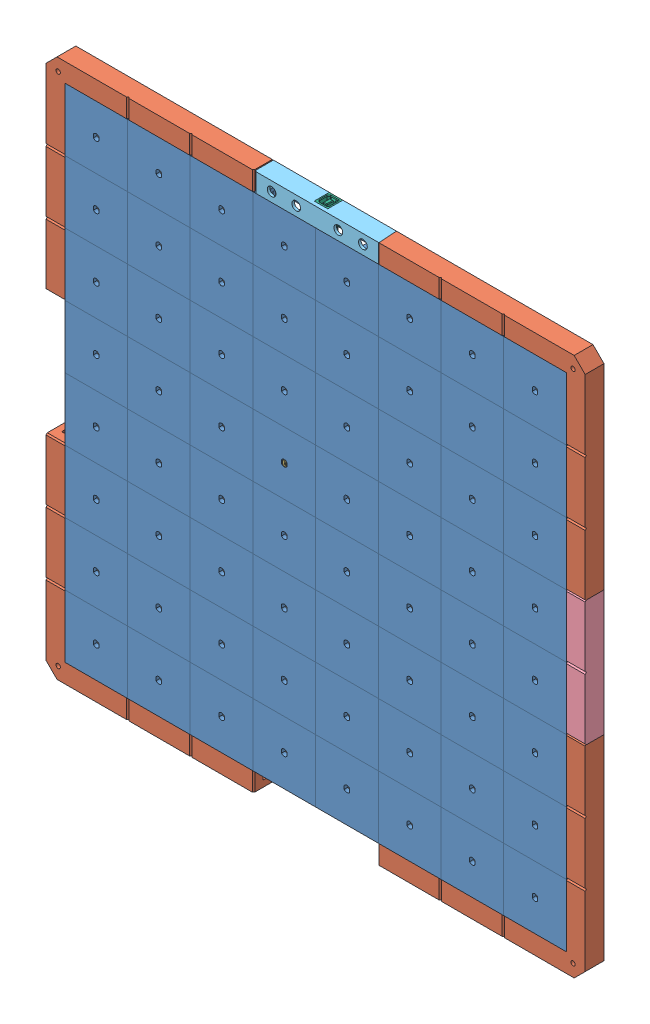
SolidWorks assembly ChessBoardAssem, configuration Default. Lengths in mm.
Overall size (430 430 16.78).
72 component instances, 6 part files, 162 mates.
Components (placement in the parent):
- ChessField-1: ChessField [Default] at (20.7333 30.8227 34.0737) size (50 50 15)
- ChessField-3: ChessField [Default] at (320.7333 30.8227 34.0737) size (50 50 15)
- ChessField-6: ChessField [Default] at (320.7333 80.8227 34.0737) size (50 50 15)
- ChessField-8: ChessField [Default] at (370.7333 130.8227 34.0737) size (50 50 15)
- ChessField-9: ChessField [Default] at (220.7333 30.8227 34.0737) size (50 50 15)
- ChessField-10: ChessField [Default] at (370.7333 80.8227 34.0737) size (50 50 15)
- ChessField-11: ChessField [Default] at (70.7333 80.8227 34.0737) size (50 50 15)
- ChessField-12: ChessField [Default] at (270.7333 30.8227 34.0737) size (50 50 15)
- ChessField-13: ChessField [Default] at (120.7333 30.8227 34.0737) size (50 50 15)
- ChessField-14: ChessField [Default] at (370.7333 180.8227 34.0737) size (50 50 15)
- ChessField-16: ChessField [Default] at (70.7333 30.8227 34.0737) size (50 50 15)
- ChessField-18: ChessField [Default] at (170.7333 80.8227 34.0737) size (50 50 15)
- ChessField-20: ChessField [Default] at (170.7333 130.8227 34.0737) size (50 50 15)
- ChessField-21: ChessField [Default] at (270.7333 130.8227 34.0737) size (50 50 15)
- ChessField-25: ChessField [Default] at (320.7333 180.8227 34.0737) size (50 50 15)
- ChessField-29: ChessField [Default] at (220.7333 180.8227 34.0737) size (50 50 15)
- ChessField-34: ChessField [Default] at (220.7333 80.8227 34.0737) size (50 50 15)
- ChessField-38: ChessField [Default] at (120.7333 130.8227 34.0737) size (50 50 15)
- ChessField-40: ChessField [Default] at (20.7333 80.8227 34.0737) size (50 50 15)
- ChessField-41: ChessField [Default] at (70.7333 130.8227 34.0737) size (50 50 15)
- ChessField-43: ChessField [Default] at (120.7333 180.8227 34.0737) size (50 50 15)
- ChessField-44: ChessField [Default] at (120.7333 80.8227 34.0737) size (50 50 15)
- ChessField-45: ChessField [Default] at (70.7333 180.8227 34.0737) size (50 50 15)
- ChessField-46: ChessField [Default] at (20.7333 180.8227 34.0737) size (50 50 15)
- ChessField-51: ChessField [Default] at (20.7333 130.8227 34.0737) size (50 50 15)
- ChessField-53: ChessField [Default] at (170.7333 180.8227 34.0737) size (50 50 15)
- ChessField-56: ChessField [Default] at (270.7333 180.8227 34.0737) size (50 50 15)
- ChessField-57: ChessField [Default] at (320.7333 130.8227 34.0737) size (50 50 15)
- ChessField-58: ChessField [Default] at (270.7333 80.8227 34.0737) size (50 50 15)
- ChessField-62: ChessField [Default] at (220.7333 130.8227 34.0737) size (50 50 15)
- ChessField-63: ChessField [Default] at (170.7333 30.8227 34.0737) size (50 50 15)
- ChessField-64: ChessField [Default] at (370.7333 30.8227 34.0737) size (50 50 15)
- ChessField-98: ChessField [Default] at (370.7333 230.8227 34.0737) size (50 50 15)
- ChessField-99: ChessField [Default] at (20.7333 380.8227 34.0737) size (50 50 15)
- ChessField-100: ChessField [Default] at (170.7333 380.8227 34.0737) size (50 50 15)
- ChessField-101: ChessField [Default] at (20.7333 330.8227 34.0737) size (50 50 15)
- ChessField-102: ChessField [Default] at (20.7333 280.8227 34.0737) size (50 50 15)
- ChessField-103: ChessField [Default] at (70.7333 380.8227 34.0737) size (50 50 15)
- ChessField-104: ChessField [Default] at (70.7333 330.8227 34.0737) size (50 50 15)
- ChessField-105: ChessField [Default] at (120.7333 380.8227 34.0737) size (50 50 15)
- ChessField-106: ChessField [Default] at (120.7333 330.8227 34.0737) size (50 50 15)
- ChessField-107: ChessField [Default] at (120.7333 280.8227 34.0737) size (50 50 15)
- ChessField-108: ChessField [Default] at (220.7333 380.8227 34.0737) size (50 50 15)
- ChessField-109: ChessField [Default] at (170.7333 330.8227 34.0737) size (50 50 15)
- ChessField-110: ChessField [Default] at (270.7333 330.8227 34.0737) size (50 50 15)
- ChessField-111: ChessField [Default] at (220.7333 330.8227 34.0737) size (50 50 15)
- ChessField-112: ChessField [Default] at (220.7333 280.8227 34.0737) size (50 50 15)
- ChessField-113: ChessField [Default] at (320.7333 380.8227 34.0737) size (50 50 15)
- ChessField-114: ChessField [Default] at (320.7333 330.8227 34.0737) size (50 50 15)
- ChessField-115: ChessField [Default] at (270.7333 280.8227 34.0737) size (50 50 15)
- ChessField-116: ChessField [Default] at (270.7333 380.8227 34.0737) size (50 50 15)
- ChessField-117: ChessField [Default] at (370.7333 330.8227 34.0737) size (50 50 15)
- ChessField-118: ChessField [Default] at (320.7333 280.8227 34.0737) size (50 50 15)
- ChessField-119: ChessField [Default] at (370.7333 380.8227 34.0737) size (50 50 15)
- ChessField-120: ChessField [Default] at (370.7333 280.8227 34.0737) size (50 50 15)
- ChessField-121: ChessField [Default] at (320.7333 230.8227 34.0737) size (50 50 15)
- ChessField-122: ChessField [Default] at (270.7333 230.8227 34.0737) size (50 50 15)
- ChessField-123: ChessField [Default] at (220.7333 230.8227 34.0737) size (50 50 15)
- ChessField-124: ChessField [Default] at (20.7333 230.8227 34.0737) size (50 50 15)
- ChessField-125: ChessField [Default] at (170.7333 230.8227 34.0737) size (50 50 15)
- ChessField-126: ChessField [Default] at (120.7333 230.8227 34.0737) size (50 50 15)
- ChessField-127: ChessField [Default] at (70.7333 230.8227 34.0737) size (50 50 15)
- ChessField-128: ChessField [Default] at (70.7333 280.8227 34.0737) size (50 50 15)
- ChessField-129: ChessField [Default] at (170.7333 280.8227 34.0737) size (50 50 15)
- ChessFrameCorner-2: ChessFrameCorner [Default] at (395.7333 5.8227 34.0737) size (165.5 165.5 15)
- ChessFrameCorner-3: ChessFrameCorner [Default] at (395.7333 405.8227 34.0737) x (0 1 0) z (0 0 1) size (165.5 165.5 15)
- ChessFrameCorner-5: ChessFrameCorner [Default] at (-4.2667 405.8227 34.0737) x (-1 0 0) z (0 0 1) size (165.5 165.5 15)
- ChessFrameCorner-6: ChessFrameCorner [Default] at (-4.2667 5.8227 34.0737) x (0 -1 0) z (0 0 1) size (165.5 165.5 15)
- photoresistor-1: photoresistor [Default] at (171.0833 230.8064 49.0837) x (-1 0 0) z (0 -1 0) size (3.8 11.1 4.55)
- ChessFrameMiddleStd-2: ChessFrameMiddleStd [Default] at (403.2333 205.8227 34.0737) x (0 -1 0) z (0 0 1) size (114.9 15 15)
- ChessFrameMiddleButsPower-1: ChessFrameMiddleButsPower [Default] at (197.0733 413.3227 34.0737) size (114.9 15 15)
- USB-type-B(USBR-B-S-F-O-TH).step-1: USB-type-B(USBR-B-S-F-O-TH).step [Default] at (197.1483 412.6727 40.1237) x (0 0 -1) z (0 1 0) size (15.17 14.72 16.3)
Mates (geometry in assembly coordinates):
- Coincident1: coincident anti-aligned: plane of ChessField-1 through (45.7333 5.8227 49.0737) normal (1 0 0); plane of ChessField-16 through (45.7333 5.8227 49.0737) normal (-1 0 0)
- Coincident2: coincident anti-aligned: line of ChessField-1 through (45.7333 5.8227 49.0737) axis (0 1 0); line of ChessField-16 through (45.7333 55.8227 49.0737) axis (0 -1 0)
- Coincident3: coincident aligned: line of ChessField-1 through (45.7333 5.8227 49.0737) axis (0 0 -1); line of ChessField-16 through (45.7333 5.8227 49.0737) axis (0 0 -1)
- Coincident4: coincident anti-aligned: plane of ChessField-13 through (95.7333 5.8227 49.0737) normal (-1 0 0); plane of ChessField-16 through (95.7333 5.8227 49.0737) normal (1 0 0)
- Coincident6: coincident anti-aligned: line of ChessField-13 through (95.7333 55.8227 49.0737) axis (0 -1 0); line of ChessField-16 through (95.7333 5.8227 49.0737) axis (0 1 0)
- Coincident7: coincident aligned: line of ChessField-13 through (95.7333 5.8227 49.0737) axis (0 0 -1); line of ChessField-16 through (95.7333 5.8227 49.0737) axis (0 0 -1)
- Coincident8: coincident anti-aligned: plane of ChessField-13 through (145.7333 5.8227 49.0737) normal (1 0 0); plane of ChessField-63 through (145.7333 5.8227 49.0737) normal (-1 0 0)
- Coincident9: coincident anti-aligned: line of ChessField-13 through (145.7333 5.8227 49.0737) axis (0 1 0); line of ChessField-63 through (145.7333 55.8227 49.0737) axis (0 -1 0)
- Coincident10: coincident aligned: line of ChessField-13 through (145.7333 5.8227 49.0737) axis (0 0 -1); line of ChessField-63 through (145.7333 5.8227 49.0737) axis (0 0 -1)
- Coincident11: coincident anti-aligned: plane of ChessField-9 through (195.7333 5.8227 49.0737) normal (-1 0 0); plane of ChessField-63 through (195.7333 5.8227 49.0737) normal (1 0 0)
- Coincident12: coincident anti-aligned: line of ChessField-9 through (195.7333 55.8227 49.0737) axis (0 -1 0); line of ChessField-63 through (195.7333 5.8227 49.0737) axis (0 1 0)
- Coincident13: coincident aligned: line of ChessField-9 through (195.7333 5.8227 49.0737) axis (0 0 -1); line of ChessField-63 through (195.7333 5.8227 49.0737) axis (0 0 -1)
- Coincident14: coincident anti-aligned: plane of ChessField-9 through (245.7333 5.8227 49.0737) normal (1 0 0); plane of ChessField-12 through (245.7333 5.8227 49.0737) normal (-1 0 0)
- Coincident15: coincident anti-aligned: line of ChessField-9 through (245.7333 5.8227 49.0737) axis (0 1 0); line of ChessField-12 through (245.7333 55.8227 49.0737) axis (0 -1 0)
- Coincident16: coincident aligned: line of ChessField-9 through (245.7333 5.8227 49.0737) axis (0 0 -1); line of ChessField-12 through (245.7333 5.8227 49.0737) axis (0 0 -1)
- Coincident17: coincident anti-aligned: line of ChessField-3 through (295.7333 55.8227 49.0737) axis (0 -1 0); line of ChessField-12 through (295.7333 5.8227 49.0737) axis (0 1 0)
- Coincident18: coincident aligned: line of ChessField-3 through (295.7333 5.8227 49.0737) axis (0 0 -1); line of ChessField-12 through (295.7333 5.8227 49.0737) axis (0 0 -1)
- Coincident19: coincident anti-aligned: line of ChessField-3 through (345.7333 5.8227 49.0737) axis (0 1 0); line of ChessField-64 through (345.7333 55.8227 49.0737) axis (0 -1 0)
- Coincident20: coincident aligned: line of ChessField-3 through (345.7333 5.8227 49.0737) axis (0 0 -1); line of ChessField-64 through (345.7333 5.8227 49.0737) axis (0 0 -1)
- Coincident21: coincident anti-aligned: line of ChessField-10 through (345.7333 55.8227 49.0737) axis (1 0 0); line of ChessField-64 through (395.7333 55.8227 49.0737) axis (-1 0 0)
- Coincident22: coincident aligned: line of ChessField-3 through (345.7333 55.8227 49.0737) axis (0 0 -1); line of ChessField-10 through (345.7333 55.8227 49.0737) axis (0 0 -1)
- Coincident23: coincident anti-aligned: line of ChessField-3 through (345.7333 55.8227 49.0737) axis (-1 0 0); line of ChessField-6 through (295.7333 55.8227 49.0737) axis (1 0 0)
- Coincident24: coincident: line of ChessField-6 through (295.7333 55.8227 49.0737) axis (0 0 -1); plane of ChessField-12 through (245.7333 55.8227 49.0737) normal (0 1 0)
- Coincident25: coincident anti-aligned: line of ChessField-12 through (295.7333 55.8227 49.0737) axis (-1 0 0); line of ChessField-58 through (245.7333 55.8227 49.0737) axis (1 0 0)
- Coincident26: coincident aligned: line of ChessField-9 through (245.7333 55.8227 49.0737) axis (0 0 -1); line of ChessField-58 through (245.7333 55.8227 49.0737) axis (0 0 -1)
- Coincident27: coincident anti-aligned: line of ChessField-9 through (245.7333 55.8227 49.0737) axis (-1 0 0); line of ChessField-34 through (195.7333 55.8227 49.0737) axis (1 0 0)
- Coincident28: coincident aligned: line of ChessField-9 through (195.7333 55.8227 49.0737) axis (0 0 -1); line of ChessField-34 through (195.7333 55.8227 49.0737) axis (0 0 -1)
- Coincident29: coincident anti-aligned: line of ChessField-18 through (145.7333 55.8227 49.0737) axis (1 0 0); line of ChessField-63 through (195.7333 55.8227 49.0737) axis (-1 0 0)
- Coincident30: coincident aligned: line of ChessField-13 through (145.7333 55.8227 49.0737) axis (0 0 -1); line of ChessField-18 through (145.7333 55.8227 49.0737) axis (0 0 -1)
- Coincident31: coincident anti-aligned: line of ChessField-13 through (145.7333 55.8227 49.0737) axis (-1 0 0); line of ChessField-44 through (95.7333 55.8227 49.0737) axis (1 0 0)
- Coincident32: coincident aligned: line of ChessField-16 through (95.7333 55.8227 49.0737) axis (0 0 -1); line of ChessField-44 through (95.7333 55.8227 49.0737) axis (0 0 -1)
- Coincident33: coincident anti-aligned: line of ChessField-11 through (45.7333 55.8227 49.0737) axis (1 0 0); line of ChessField-16 through (95.7333 55.8227 49.0737) axis (-1 0 0)
- Coincident35: coincident aligned: line of ChessField-1 through (45.7333 55.8227 49.0737) axis (0 0 -1); line of ChessField-11 through (45.7333 55.8227 49.0737) axis (0 0 -1)
- Coincident36: coincident anti-aligned: line of ChessField-1 through (45.7333 55.8227 49.0737) axis (-1 0 0); line of ChessField-40 through (-4.2667 55.8227 49.0737) axis (1 0 0)
- Coincident37: coincident aligned: line of ChessField-1 through (-4.2667 55.8227 49.0737) axis (0 0 -1); line of ChessField-40 through (-4.2667 55.8227 49.0737) axis (0 0 -1)
- Coincident38: coincident anti-aligned: line of ChessField-40 through (45.7333 105.8227 49.0737) axis (-1 0 0); line of ChessField-51 through (-4.2667 105.8227 49.0737) axis (1 0 0)
- Coincident39: coincident aligned: line of ChessField-40 through (45.7333 105.8227 49.0737) axis (0 0 -1); line of ChessField-51 through (45.7333 105.8227 49.0737) axis (0 0 -1)
- Coincident40: coincident anti-aligned: line of ChessField-11 through (95.7333 105.8227 49.0737) axis (-1 0 0); line of ChessField-41 through (45.7333 105.8227 49.0737) axis (1 0 0)
- Coincident41: coincident aligned: line of ChessField-41 through (95.7333 105.8227 49.0737) axis (0 0 -1); line of ChessField-44 through (95.7333 105.8227 49.0737) axis (0 0 -1)
- Coincident42: coincident anti-aligned: line of ChessField-38 through (95.7333 105.8227 49.0737) axis (1 0 0); line of ChessField-44 through (145.7333 105.8227 49.0737) axis (-1 0 0)
- Coincident43: coincident aligned: line of ChessField-18 through (145.7333 105.8227 49.0737) axis (0 0 -1); line of ChessField-38 through (145.7333 105.8227 49.0737) axis (0 0 -1)
- Coincident44: coincident anti-aligned: line of ChessField-18 through (195.7333 105.8227 49.0737) axis (-1 0 0); line of ChessField-20 through (145.7333 105.8227 49.0737) axis (1 0 0)
- Coincident45: coincident aligned: line of ChessField-20 through (195.7333 105.8227 49.0737) axis (0 0 -1); line of ChessField-34 through (195.7333 105.8227 49.0737) axis (0 0 -1)
- Coincident46: coincident anti-aligned: line of ChessField-34 through (245.7333 105.8227 49.0737) axis (-1 0 0); line of ChessField-62 through (195.7333 105.8227 49.0737) axis (1 0 0)
- Coincident47: coincident aligned: line of ChessField-58 through (245.7333 105.8227 49.0737) axis (0 0 -1); line of ChessField-62 through (245.7333 105.8227 49.0737) axis (0 0 -1)
- Coincident48: coincident anti-aligned: line of ChessField-21 through (245.7333 105.8227 49.0737) axis (1 0 0); line of ChessField-58 through (295.7333 105.8227 49.0737) axis (-1 0 0)
- Coincident49: coincident: plane of ChessField-6 through (295.7333 105.8227 49.0737) normal (0 1 0); line of ChessField-21 through (295.7333 105.8227 49.0737) axis (0 0 -1)
- Coincident50: coincident anti-aligned: line of ChessField-6 through (345.7333 105.8227 49.0737) axis (-1 0 0); line of ChessField-57 through (295.7333 105.8227 49.0737) axis (1 0 0)
- Coincident51: coincident aligned: line of ChessField-6 through (345.7333 105.8227 49.0737) axis (0 0 -1); line of ChessField-57 through (345.7333 105.8227 49.0737) axis (0 0 -1)
- Coincident52: coincident anti-aligned: line of ChessField-8 through (345.7333 105.8227 49.0737) axis (1 0 0); line of ChessField-10 through (395.7333 105.8227 49.0737) axis (-1 0 0)
- Coincident53: coincident aligned: line of ChessField-8 through (395.7333 105.8227 49.0737) axis (0 0 -1); line of ChessField-10 through (395.7333 105.8227 49.0737) axis (0 0 -1)
- Coincident54: coincident anti-aligned: line of ChessField-8 through (395.7333 155.8227 49.0737) axis (-1 0 0); line of ChessField-14 through (345.7333 155.8227 49.0737) axis (1 0 0)
- Coincident55: coincident aligned: line of ChessField-14 through (345.7333 155.8227 49.0737) axis (0 0 -1); line of ChessField-57 through (345.7333 155.8227 49.0737) axis (0 0 -1)
- Coincident56: coincident anti-aligned: line of ChessField-25 through (295.7333 155.8227 49.0737) axis (1 0 0); line of ChessField-57 through (345.7333 155.8227 49.0737) axis (-1 0 0)
- Coincident57: coincident aligned: line of ChessField-21 through (295.7333 155.8227 49.0737) axis (0 0 -1); line of ChessField-25 through (295.7333 155.8227 49.0737) axis (0 0 -1)
- Coincident58: coincident anti-aligned: line of ChessField-21 through (295.7333 155.8227 49.0737) axis (-1 0 0); line of ChessField-56 through (245.7333 155.8227 49.0737) axis (1 0 0)
- Coincident59: coincident aligned: line of ChessField-56 through (245.7333 155.8227 49.0737) axis (0 0 -1); line of ChessField-62 through (245.7333 155.8227 49.0737) axis (0 0 -1)
- Coincident60: coincident anti-aligned: line of ChessField-29 through (195.7333 155.8227 49.0737) axis (1 0 0); line of ChessField-62 through (245.7333 155.8227 49.0737) axis (-1 0 0)
- Coincident62: coincident aligned: line of ChessField-20 through (195.7333 155.8227 49.0737) axis (0 0 -1); line of ChessField-29 through (195.7333 155.8227 49.0737) axis (0 0 -1)
- Coincident63: coincident anti-aligned: line of ChessField-20 through (195.7333 155.8227 49.0737) axis (-1 0 0); line of ChessField-53 through (145.7333 155.8227 49.0737) axis (1 0 0)
- Coincident64: coincident: plane of ChessField-29 through (195.7333 155.8227 49.0737) normal (-1 0 0); line of ChessField-53 through (195.7333 155.8227 49.0737) axis (0 0 -1)
- Coincident65: coincident anti-aligned: line of ChessField-38 through (145.7333 155.8227 49.0737) axis (-1 0 0); line of ChessField-43 through (95.7333 155.8227 49.0737) axis (1 0 0)
- Coincident66: coincident aligned: line of ChessField-41 through (95.7333 155.8227 49.0737) axis (0 0 -1); line of ChessField-43 through (95.7333 155.8227 49.0737) axis (0 0 -1)
- Coincident67: coincident anti-aligned: line of ChessField-41 through (95.7333 155.8227 49.0737) axis (-1 0 0); line of ChessField-45 through (45.7333 155.8227 49.0737) axis (1 0 0)
- Coincident68: coincident aligned: line of ChessField-43 through (95.7333 155.8227 49.0737) axis (0 0 -1); line of ChessField-45 through (95.7333 155.8227 49.0737) axis (0 0 -1)
- Coincident69: coincident anti-aligned: line of ChessField-46 through (-4.2667 155.8227 49.0737) axis (1 0 0); line of ChessField-51 through (45.7333 155.8227 49.0737) axis (-1 0 0)
- Coincident70: coincident aligned: line of ChessField-46 through (-4.2667 155.8227 49.0737) axis (0 0 -1); line of ChessField-51 through (-4.2667 155.8227 49.0737) axis (0 0 -1)
- Coincident139: coincident anti-aligned: line of ChessField-14 through (345.7333 205.8227 49.0737) axis (0 -1 0); line of ChessField-25 through (345.7333 155.8227 49.0737) axis (0 1 0)
- Coincident140: coincident anti-aligned: line of ChessField-8 through (345.7333 155.8227 49.0737) axis (0 -1 0); line of ChessField-57 through (345.7333 105.8227 49.0737) axis (0 1 0)
- Coincident141: coincident anti-aligned: plane of ChessField-123 through (195.7333 205.8227 49.0737) normal (-1 0 0); plane of ChessField-125 through (195.7333 205.8227 49.0737) normal (1 0 0)
- Coincident142: coincident aligned: line of ChessField-109 through (195.7333 305.8227 49.0737) axis (0 0 -1); line of ChessField-112 through (195.7333 305.8227 49.0737) axis (0 0 -1)
- Coincident143: coincident anti-aligned: line of ChessField-110 through (245.7333 305.8227 49.0737) axis (1 0 0); line of ChessField-115 through (295.7333 305.8227 49.0737) axis (-1 0 0)
- Coincident144: coincident: line of ChessField-110 through (295.7333 305.8227 49.0737) axis (0 0 -1); plane of ChessField-118 through (295.7333 305.8227 49.0737) normal (0 1 0)
- Coincident145: coincident anti-aligned: line of ChessField-114 through (295.7333 305.8227 49.0737) axis (1 0 0); line of ChessField-118 through (345.7333 305.8227 49.0737) axis (-1 0 0)
- Coincident146: coincident anti-aligned: line of ChessField-109 through (145.7333 305.8227 49.0737) axis (1 0 0); line of ChessField-129 through (195.7333 305.8227 49.0737) axis (-1 0 0)
- Coincident147: coincident aligned: line of ChessField-111 through (245.7333 305.8227 49.0737) axis (0 0 -1); line of ChessField-115 through (245.7333 305.8227 49.0737) axis (0 0 -1)
- Coincident148: coincident aligned: line of ChessField-114 through (345.7333 305.8227 49.0737) axis (0 0 -1); line of ChessField-118 through (345.7333 305.8227 49.0737) axis (0 0 -1)
- Coincident149: coincident anti-aligned: line of ChessField-117 through (345.7333 305.8227 49.0737) axis (1 0 0); line of ChessField-120 through (395.7333 305.8227 49.0737) axis (-1 0 0)
- Coincident150: coincident aligned: line of ChessField-104 through (95.7333 305.8227 49.0737) axis (0 0 -1); line of ChessField-107 through (95.7333 305.8227 49.0737) axis (0 0 -1)
- Coincident151: coincident anti-aligned: line of ChessField-111 through (195.7333 305.8227 49.0737) axis (1 0 0); line of ChessField-112 through (245.7333 305.8227 49.0737) axis (-1 0 0)
- Coincident152: coincident anti-aligned: line of ChessField-106 through (95.7333 305.8227 49.0737) axis (1 0 0); line of ChessField-107 through (145.7333 305.8227 49.0737) axis (-1 0 0)
- Coincident153: coincident aligned: line of ChessField-106 through (145.7333 305.8227 49.0737) axis (0 0 -1); line of ChessField-129 through (145.7333 305.8227 49.0737) axis (0 0 -1)
- Coincident154: coincident anti-aligned: line of ChessField-104 through (45.7333 305.8227 49.0737) axis (1 0 0); line of ChessField-128 through (95.7333 305.8227 49.0737) axis (-1 0 0)
- Coincident155: coincident aligned: line of ChessField-108 through (195.7333 355.8227 49.0737) axis (0 0 -1); line of ChessField-109 through (195.7333 355.8227 49.0737) axis (0 0 -1)
- Coincident156: coincident anti-aligned: line of ChessField-99 through (-4.2667 355.8227 49.0737) axis (1 0 0); line of ChessField-101 through (45.7333 355.8227 49.0737) axis (-1 0 0)
- Coincident157: coincident aligned: line of ChessField-104 through (95.7333 355.8227 49.0737) axis (0 0 -1); line of ChessField-105 through (95.7333 355.8227 49.0737) axis (0 0 -1)
- Coincident158: coincident aligned: line of ChessField-111 through (245.7333 355.8227 49.0737) axis (0 0 -1); line of ChessField-116 through (245.7333 355.8227 49.0737) axis (0 0 -1)
- Coincident159: coincident anti-aligned: line of ChessField-103 through (45.7333 355.8227 49.0737) axis (1 0 0); line of ChessField-104 through (95.7333 355.8227 49.0737) axis (-1 0 0)
- Coincident160: coincident anti-aligned: line of ChessField-108 through (195.7333 355.8227 49.0737) axis (1 0 0); line of ChessField-111 through (245.7333 355.8227 49.0737) axis (-1 0 0)
- Coincident161: coincident aligned: line of ChessField-103 through (95.7333 355.8227 49.0737) axis (0 0 -1); line of ChessField-105 through (95.7333 355.8227 49.0737) axis (0 0 -1)
- Coincident162: coincident: line of ChessField-100 through (195.7333 355.8227 49.0737) axis (0 0 -1); plane of ChessField-108 through (195.7333 355.8227 49.0737) normal (-1 0 0)
- Coincident163: coincident anti-aligned: line of ChessField-110 through (295.7333 355.8227 49.0737) axis (-1 0 0); line of ChessField-116 through (245.7333 355.8227 49.0737) axis (1 0 0)
- Coincident164: coincident anti-aligned: line of ChessField-100 through (145.7333 355.8227 49.0737) axis (1 0 0); line of ChessField-109 through (195.7333 355.8227 49.0737) axis (-1 0 0)
- Coincident165: coincident anti-aligned: line of ChessField-105 through (95.7333 355.8227 49.0737) axis (1 0 0); line of ChessField-106 through (145.7333 355.8227 49.0737) axis (-1 0 0)
- Coincident166: coincident aligned: line of ChessField-120 through (345.7333 255.8227 49.0737) axis (0 0 -1); line of ChessField-121 through (345.7333 255.8227 49.0737) axis (0 0 -1)
- Coincident167: coincident anti-aligned: line of ChessField-118 through (295.7333 255.8227 49.0737) axis (1 0 0); line of ChessField-121 through (345.7333 255.8227 49.0737) axis (-1 0 0)
- Coincident168: coincident aligned: line of ChessField-126 through (95.7333 205.8227 49.0737) axis (0 0 -1); line of ChessField-127 through (95.7333 205.8227 49.0737) axis (0 0 -1)
- Coincident169: coincident anti-aligned: plane of ChessField-125 through (145.7333 205.8227 49.0737) normal (-1 0 0); plane of ChessField-126 through (145.7333 205.8227 49.0737) normal (1 0 0)
- Coincident170: coincident anti-aligned: line of ChessField-125 through (145.7333 255.8227 49.0737) axis (0 -1 0); line of ChessField-126 through (145.7333 205.8227 49.0737) axis (0 1 0)
- Coincident171: coincident aligned: line of ChessField-125 through (145.7333 205.8227 49.0737) axis (0 0 -1); line of ChessField-126 through (145.7333 205.8227 49.0737) axis (0 0 -1)
- Coincident172: coincident aligned: line of ChessField-122 through (245.7333 205.8227 49.0737) axis (0 0 -1); line of ChessField-123 through (245.7333 205.8227 49.0737) axis (0 0 -1)
- Coincident173: coincident aligned: line of ChessField-121 through (295.7333 205.8227 49.0737) axis (0 0 -1); line of ChessField-122 through (295.7333 205.8227 49.0737) axis (0 0 -1)
- Coincident174: coincident aligned: line of ChessField-123 through (195.7333 205.8227 49.0737) axis (0 0 -1); line of ChessField-125 through (195.7333 205.8227 49.0737) axis (0 0 -1)
- Coincident175: coincident anti-aligned: line of ChessField-121 through (295.7333 255.8227 49.0737) axis (0 -1 0); line of ChessField-122 through (295.7333 205.8227 49.0737) axis (0 1 0)
- Coincident176: coincident anti-aligned: line of ChessField-98 through (345.7333 255.8227 49.0737) axis (0 -1 0); line of ChessField-121 through (345.7333 205.8227 49.0737) axis (0 1 0)
- Coincident177: coincident aligned: line of ChessField-98 through (345.7333 205.8227 49.0737) axis (0 0 -1); line of ChessField-121 through (345.7333 205.8227 49.0737) axis (0 0 -1)
- Coincident178: coincident anti-aligned: line of ChessField-98 through (395.7333 255.8227 49.0737) axis (-1 0 0); line of ChessField-120 through (345.7333 255.8227 49.0737) axis (1 0 0)
- Coincident179: coincident anti-aligned: plane of ChessField-122 through (245.7333 205.8227 49.0737) normal (-1 0 0); plane of ChessField-123 through (245.7333 205.8227 49.0737) normal (1 0 0)
- Coincident180: coincident anti-aligned: line of ChessField-122 through (245.7333 255.8227 49.0737) axis (0 -1 0); line of ChessField-123 through (245.7333 205.8227 49.0737) axis (0 1 0)
- Coincident181: coincident anti-aligned: line of ChessField-123 through (195.7333 255.8227 49.0737) axis (0 -1 0); line of ChessField-125 through (195.7333 205.8227 49.0737) axis (0 1 0)
- Coincident182: coincident anti-aligned: line of ChessField-125 through (195.7333 255.8227 49.0737) axis (-1 0 0); line of ChessField-129 through (145.7333 255.8227 49.0737) axis (1 0 0)
- Coincident183: coincident: line of ChessField-118 through (295.7333 255.8227 49.0737) axis (0 0 -1); plane of ChessField-122 through (245.7333 255.8227 49.0737) normal (0 1 0)
- Coincident184: coincident anti-aligned: line of ChessField-115 through (245.7333 255.8227 49.0737) axis (1 0 0); line of ChessField-122 through (295.7333 255.8227 49.0737) axis (-1 0 0)
- Coincident185: coincident anti-aligned: line of ChessField-112 through (195.7333 255.8227 49.0737) axis (1 0 0); line of ChessField-123 through (245.7333 255.8227 49.0737) axis (-1 0 0)
- Coincident186: coincident aligned: line of ChessField-112 through (195.7333 255.8227 49.0737) axis (0 0 -1); line of ChessField-123 through (195.7333 255.8227 49.0737) axis (0 0 -1)
- Coincident187: coincident aligned: line of ChessField-115 through (245.7333 255.8227 49.0737) axis (0 0 -1); line of ChessField-123 through (245.7333 255.8227 49.0737) axis (0 0 -1)
- Coincident188: coincident aligned: line of ChessField-117 through (395.7333 305.8227 49.0737) axis (0 0 -1); line of ChessField-120 through (395.7333 305.8227 49.0737) axis (0 0 -1)
- Coincident189: coincident aligned: line of ChessField-107 through (95.7333 255.8227 49.0737) axis (0 0 -1); line of ChessField-127 through (95.7333 255.8227 49.0737) axis (0 0 -1)
- Coincident190: coincident anti-aligned: line of ChessField-102 through (-4.2667 255.8227 49.0737) axis (1 0 0); line of ChessField-124 through (45.7333 255.8227 49.0737) axis (-1 0 0)
- Coincident191: coincident anti-aligned: line of ChessField-101 through (-4.2667 305.8227 49.0737) axis (1 0 0); line of ChessField-102 through (45.7333 305.8227 49.0737) axis (-1 0 0)
- Coincident192: coincident anti-aligned: line of ChessField-127 through (95.7333 255.8227 49.0737) axis (-1 0 0); line of ChessField-128 through (45.7333 255.8227 49.0737) axis (1 0 0)
- Coincident193: coincident anti-aligned: line of ChessField-107 through (95.7333 255.8227 49.0737) axis (1 0 0); line of ChessField-126 through (145.7333 255.8227 49.0737) axis (-1 0 0)
- Coincident194: coincident aligned: line of ChessField-101 through (45.7333 305.8227 49.0737) axis (0 0 -1); line of ChessField-102 through (45.7333 305.8227 49.0737) axis (0 0 -1)
- Coincident195: coincident aligned: line of ChessField-126 through (145.7333 255.8227 49.0737) axis (0 0 -1); line of ChessField-129 through (145.7333 255.8227 49.0737) axis (0 0 -1)
- Coincident196: coincident aligned: line of ChessField-102 through (-4.2667 255.8227 49.0737) axis (0 0 -1); line of ChessField-124 through (-4.2667 255.8227 49.0737) axis (0 0 -1)
- Coincident197: coincident aligned: line of ChessField-124 through (45.7333 255.8227 49.0737) axis (0 0 -1); line of ChessField-128 through (45.7333 255.8227 49.0737) axis (0 0 -1)
- Coincident198: coincident anti-aligned: line of ChessField-113 through (345.7333 355.8227 49.0737) axis (0 1 0); line of ChessField-119 through (345.7333 405.8227 49.0737) axis (0 -1 0)
- Coincident199: coincident anti-aligned: line of ChessField-114 through (345.7333 305.8227 49.0737) axis (0 1 0); line of ChessField-117 through (345.7333 355.8227 49.0737) axis (0 -1 0)
- Coincident200: coincident anti-aligned: line of ChessField-113 through (295.7333 355.8227 49.0737) axis (1 0 0); line of ChessField-114 through (345.7333 355.8227 49.0737) axis (-1 0 0)
- Coincident201: coincident aligned: line of ChessField-114 through (345.7333 355.8227 49.0737) axis (0 0 -1); line of ChessField-119 through (345.7333 355.8227 49.0737) axis (0 0 -1)
- Coincident202: coincident anti-aligned: line of ChessField-117 through (395.7333 355.8227 49.0737) axis (-1 0 0); line of ChessField-119 through (345.7333 355.8227 49.0737) axis (1 0 0)
- Coincident203: coincident aligned: line of ChessField-110 through (295.7333 355.8227 49.0737) axis (0 0 -1); line of ChessField-113 through (295.7333 355.8227 49.0737) axis (0 0 -1)
- Coincident204: coincident anti-aligned: plane of ChessField-126 through (95.7333 205.8227 49.0737) normal (-1 0 0); plane of ChessField-127 through (95.7333 205.8227 49.0737) normal (1 0 0)
- Coincident205: coincident anti-aligned: plane of ChessField-124 through (45.7333 205.8227 49.0737) normal (1 0 0); plane of ChessField-127 through (45.7333 205.8227 49.0737) normal (-1 0 0)
- Coincident206: coincident anti-aligned: line of ChessField-126 through (95.7333 255.8227 49.0737) axis (0 -1 0); line of ChessField-127 through (95.7333 205.8227 49.0737) axis (0 1 0)
- Coincident207: coincident anti-aligned: line of ChessField-124 through (45.7333 205.8227 49.0737) axis (0 1 0); line of ChessField-127 through (45.7333 255.8227 49.0737) axis (0 -1 0)
- Coincident208: coincident aligned: line of ChessField-124 through (45.7333 205.8227 49.0737) axis (0 0 -1); line of ChessField-127 through (45.7333 205.8227 49.0737) axis (0 0 -1)
- Coincident209: coincident aligned: line of ChessField-99 through (-4.2667 355.8227 49.0737) axis (0 0 -1); line of ChessField-101 through (-4.2667 355.8227 49.0737) axis (0 0 -1)
- Coincident210: coincident anti-aligned: line of ChessField-14 through (395.7333 205.8227 49.0737) axis (-1 0 0); line of ChessField-98 through (345.7333 205.8227 49.0737) axis (1 0 0)
- Coincident211: coincident aligned: line of ChessField-14 through (395.7333 205.8227 49.0737) axis (0 0 -1); line of ChessField-98 through (395.7333 205.8227 49.0737) axis (0 0 -1)
- Coincident217: coincident anti-aligned: line of ChessField-8 through (395.7333 105.8227 49.0737) axis (0 1 0); line of ChessFrameCorner-2 through (395.7333 55.0727 49.0737) axis (0 -1 0)
- Coincident218: coincident anti-aligned: line of ChessField-3 through (295.7333 5.8227 49.0737) axis (1 0 0); line of ChessFrameCorner-2 through (395.7333 5.8227 49.0737) axis (-1 0 0)
- Coincident219: coincident anti-aligned: line of ChessField-117 through (395.7333 305.8227 49.0737) axis (0 1 0); line of ChessFrameCorner-3 through (395.7333 405.8227 49.0737) axis (0 -1 0)
- Coincident220: coincident anti-aligned: line of ChessField-113 through (345.7333 405.8227 49.0737) axis (-1 0 0); line of ChessFrameCorner-3 through (346.4833 405.8227 49.0737) axis (1 0 0)
- Coincident221: coincident anti-aligned: plane of ChessField-99 through (-4.2667 355.8227 49.0737) normal (-1 0 0); plane of ChessFrameCorner-5 through (-4.2667 405.8227 49.0737) normal (1 0 0)
- Coincident222: coincident anti-aligned: plane of ChessField-99 through (-4.2667 405.8227 49.0737) normal (0 1 0); plane of ChessFrameCorner-5 through (146.2333 405.8227 49.0737) normal (0 -1 0)
- Coincident223: coincident anti-aligned: line of ChessField-99 through (45.7333 405.8227 34.0737) axis (-1 0 0); line of ChessFrameCorner-5 through (-4.2667 405.8227 34.0737) axis (1 0 0)
- Coincident224: coincident anti-aligned: plane of ChessField-1 through (-4.2667 5.8227 49.0737) normal (-1 0 0); plane of ChessFrameCorner-6 through (-4.2667 156.3227 49.0737) normal (1 0 0)
- Coincident225: coincident anti-aligned: plane of ChessField-1 through (-4.2667 5.8227 49.0737) normal (0 -1 0); plane of ChessFrameCorner-6 through (-4.2667 5.8227 49.0737) normal (0 1 0)
- Coincident226: coincident anti-aligned: line of ChessField-1 through (-4.2667 55.8227 34.0737) axis (0 -1 0); line of ChessFrameCorner-6 through (-4.2667 5.8227 34.0737) axis (0 1 0)
- Distance1: distance = 100 mm: line of ChessField-127 through (72.8833 232.1939 49.0737) axis (0 -1 0); line of photoresistor-1 through (172.8833 229.5854 49.0737) axis (0 1 0)
- Parallel1: parallel anti-aligned: plane of ChessField-127 through (68.5833 232.1939 49.0737) normal (1 0 0); plane of photoresistor-1 through (169.1833 232.0576 48.0837) normal (-1 0 0)
- Coincident231: coincident aligned: plane of ChessField-127 through (70.7333 230.8227 49.0737) normal (0 0 1); plane of photoresistor-1 through (171.0833 230.8064 49.0737) normal (0 0 1)
- Coincident232: coincident: plane of ChessField-98 through (395.7333 205.8227 49.0737) normal (1 0 0); plane of ChessFrameMiddleStd-1 through (395.7333 156.0108 49.0737) normal (-1 0 0)
- Coincident233: coincident anti-aligned: line of ChessField-98 through (395.7333 205.8227 49.0737) axis (0 1 0); line of ChessFrameMiddleStd-1 through (395.7333 255.1108 49.0737) axis (0 -1 0)
- Coincident234: coincident anti-aligned: plane of ChessField-98 through (395.7333 205.8227 49.0737) normal (1 0 0); plane of ChessFrameMiddleStd-2 through (395.7333 255.8227 49.0737) normal (-1 0 0)
- Coincident235: coincident anti-aligned: line of ChessField-14 through (395.7333 155.8227 49.0737) axis (0 1 0); line of ChessFrameMiddleStd-2 through (395.7333 204.8227 49.0737) axis (0 -1 0)
- Coincident236: coincident anti-aligned: plane of ChessField-100 through (145.7333 405.8227 49.0737) normal (0 1 0); plane of ChessFrameMiddleButs-1 through (147.0733 405.8227 49.0737) normal (0 -1 0)
- Coincident237: coincident anti-aligned: line of ChessField-100 through (195.7333 405.8227 49.0737) axis (-1 0 0); line of ChessFrameMiddleButs-1 through (148.0733 405.8227 49.0737) axis (1 0 0)
- Coincident238: coincident anti-aligned: line of ChessField-100 through (195.7333 355.8227 49.0737) axis (0 1 0); line of ChessField-108 through (195.7333 405.8227 49.0737) axis (0 -1 0)
- Coincident239: coincident anti-aligned: plane of ChessFrameMiddleButs-1 through (191.6483 410.8227 46.1237) normal (1 0 0); plane of USB-type-B(USBR-B-S-F-O-TH).step-1 through (191.6483 420.8227 46.1237) normal (-1 0 0)
- Coincident240: coincident aligned: line of ChessFrameMiddleButs-1 through (191.6483 420.8227 46.1237) axis (1 0 0); line of USB-type-B(USBR-B-S-F-O-TH).step-1 through (191.6483 420.8227 46.1237) axis (1 0 0)
